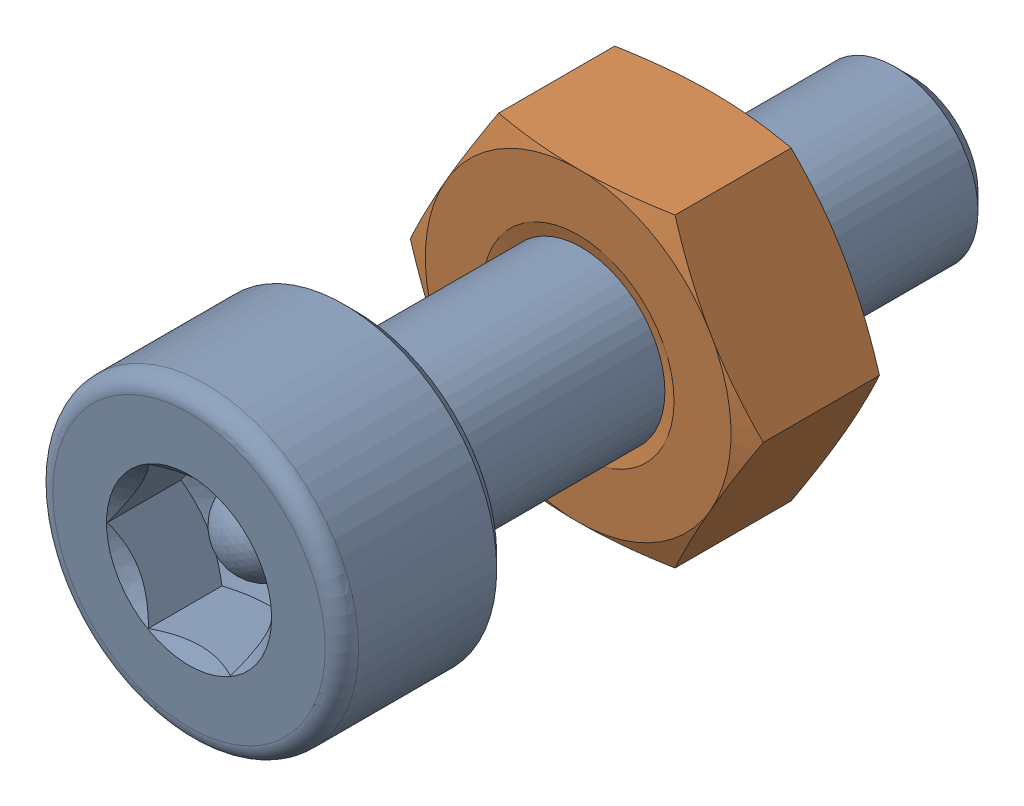
SolidWorks assembly Screw and Nut M3x010_019-1, configuration Varsayılan. Lengths in mm.
Overall size (6.35 5.5 13.14).
2 component instances, 2 part files, 0 mates.
Components (placement in the parent):
- M3x10-Screw018-1-1: M3x10-Screw018-1 [Varsayılan] at origin size (5.5 5.5 13.14)
- M3-Nut050-1-1: M3-Nut050-1 [Varsayılan] at (0 0 -4) x (-1 0 0) z (0 0 -1) size (6.35 5.5 2.4)
